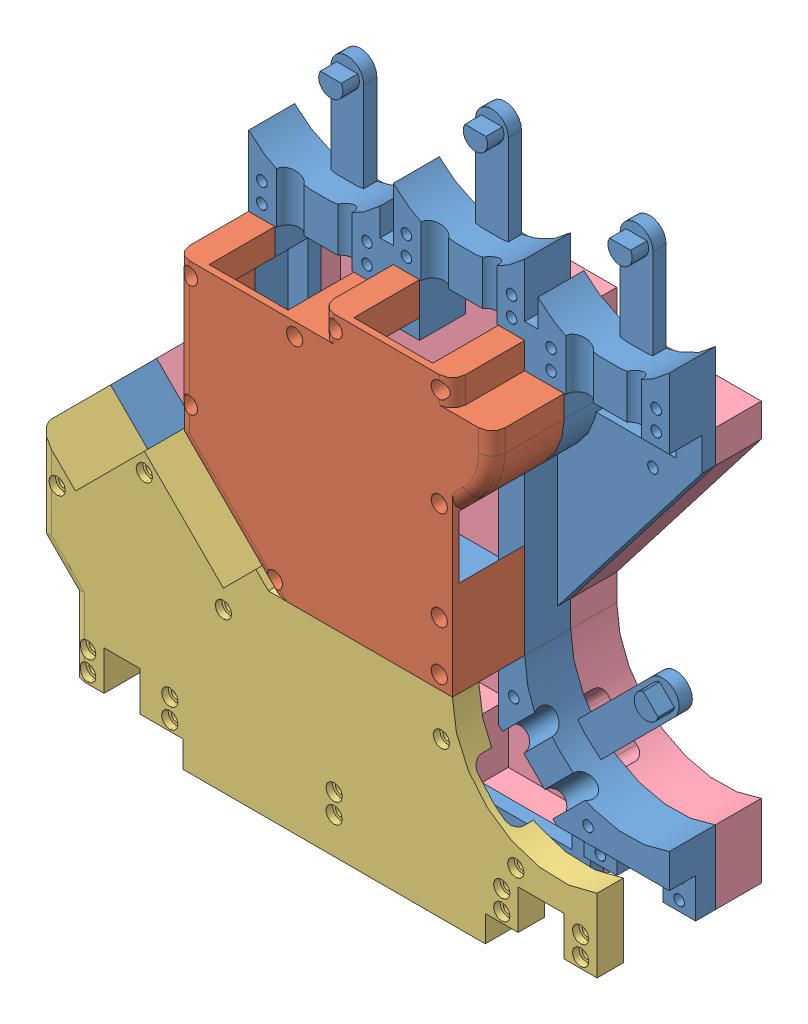
SolidWorks assembly palmM-assembly, configuration Default. Lengths in mm.
Overall size (85 94.5 25.1).
4 component instances, 4 part files, 9 mates.
Components (placement in the parent):
- palmM-middle-1: palmM-middle [Default] at (31.9405 60.3293 63.4177) size (85 94.5 7.12)
- palmM-front1-1: palmM-front1 [Default] at (59.572 98.5378 70.4177) x (1 0 0) z (0 -1 0) size (48 11.1 41.5)
- palmM-front2-1: palmM-front2 [Default] at (65.9463 79.8116 70.4177) x (1 0 0) z (0 -1 0) size (85 16 38.96)
- palmM-back-1: palmM-back [Default] at (31.9405 60.3294 56.4177) size (85 71.5 7)
Mates (geometry in assembly coordinates):
- Concentric2: concentric aligned: cylinder of palmM-middle-1 through (54.9405 125.8293 70.5347) axis (0 0 -1) radius 0.8; cylinder of palmM-front1-1 through (54.9405 125.8293 81.4177) axis (0 0 -1) radius 0.8
- Concentric3: concentric aligned: cylinder of palmM-middle-1 through (92.9405 92.3293 70.5347) axis (0 0 -1) radius 0.8; cylinder of palmM-front1-1 through (92.9405 92.3293 81.4177) axis (0 0 -1) radius 0.8
- Coincident1: coincident anti-aligned: plane of palmM-middle-1 through (31.9405 60.3293 70.4177) normal (0 0 1); plane of palmM-front1-1 through (59.572 98.5378 70.4177) normal (0 0 -1)
- Concentric4: concentric anti-aligned: cylinder of palmM-middle-1 through (34.8045 88.1076 70.5347) axis (0 0 -1) radius 0.8; cylinder of palmM-front2-1 through (34.8045 88.1076 65.4177) axis (0 0 1) radius 0.8
- Concentric5: concentric anti-aligned: cylinder of palmM-middle-1 through (76.9405 65.8293 70.5347) axis (0 0 -1) radius 0.8; cylinder of palmM-front2-1 through (76.9405 65.8293 65.4177) axis (0 0 1) radius 0.8
- Coincident2: coincident anti-aligned: plane of palmM-front2-1 through (65.9463 79.8116 70.4177) normal (0 0 -1); plane of palmM-middle-1 through (31.9405 60.3293 70.4177) normal (0 0 1)
- Concentric6: concentric aligned: cylinder of palmM-middle-1 through (76.9405 68.8293 70.5347) axis (0 0 -1) radius 0.8; cylinder of palmM-back-1 through (76.9405 68.8293 63.4177) axis (0 0 -1) radius 0.8
- Concentric7: concentric aligned: cylinder of palmM-middle-1 through (76.9405 65.8293 70.5347) axis (0 0 -1) radius 0.8; cylinder of palmM-back-1 through (76.9405 65.8293 63.4177) axis (0 0 -1) radius 0.8
- Coincident3: coincident anti-aligned: plane of palmM-middle-1 through (31.9405 60.3293 63.4177) normal (0 0 -1); plane of palmM-back-1 through (110.9405 90.3294 63.4177) normal (0 0 1)
